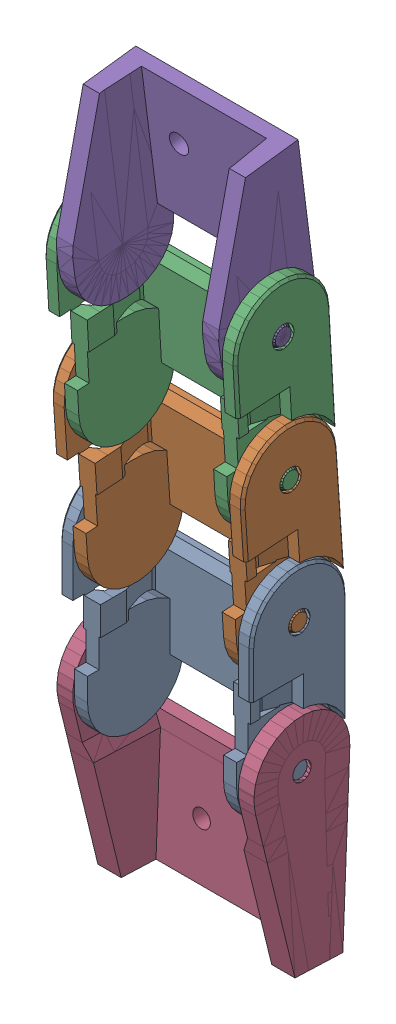
SolidWorks assembly Test Track Assembly, configuration Default. Lengths in mm.
Overall size (24.67 88.78 16.6).
5 component instances, 3 part files, 8 mates.
Components (placement in the parent):
- Main Cable Link-1: Main Cable Link [Default] at origin size (24 28 12)
- Main Cable Link-2: Main Cable Link [Default] at (0 15.9628 1.0904) x (1 0 0) z (0 -0.06815 0.997675) size (24 28 12)
- Main Cable Link-3: Main Cable Link [Default] at (0 31.9368 2.0023) x (1 0 0) z (0 -0.056992 0.998375) size (24 28 12)
- Track End Modified-1: Track End Modified [Default] at (0 15.9747 -1.2712) x (1 0 0) z (0 0.039726 0.999211) size (24.67 28.01 12)
- Track End Modified 2-1: Track End Modified 2 [Default] at (0 31.9368 2.0023) x (1 0 0) z (0 -0.99211 -0.125367) size (24 12.06 24)
Mates (geometry in assembly coordinates):
- Width1: width anti-aligned: plane of Main Cable Link-1 through (-12 0 0) normal (-1 0 0); plane of Main Cable Link-2 through (12 0 0) normal (1 0 0); plane of Main Cable Link-1 through (10.16 15.9628 1.0904) normal (1 0 0); plane of Main Cable Link-2 through (-10.16 15.9628 1.0904) normal (-1 0 0)
- Width2: width anti-aligned: plane of Main Cable Link-2 through (12 15.9628 1.0904) normal (1 0 0); plane of Main Cable Link-3 through (-12 15.9628 1.0904) normal (-1 0 0); plane of Main Cable Link-2 through (-10.16 31.9368 2.0023) normal (-1 0 0); plane of Main Cable Link-3 through (10.16 31.9368 2.0023) normal (1 0 0)
- Width3: width anti-aligned: plane of Main Cable Link-3 through (-12 31.9368 2.0023) normal (-1 0 0); plane of Track End Modified 2-1 through (12 31.9368 2.0023) normal (1 0 0); plane of Main Cable Link-3 through (10.16 31.9368 2.0023) normal (1 0 0); plane of Track End Modified 2-1 through (-10.16 31.9368 2.0023) normal (-1 0 0)
- Width4: width anti-aligned: plane of Track End Modified-1 through (-12.3367 15.9747 -1.2712) normal (-1 0 0); plane of Main Cable Link-1 through (12.3367 15.9747 -1.2712) normal (1 0 0); plane of Track End Modified-1 through (10.16 0 0) normal (1 0 0); plane of Main Cable Link-1 through (-10.16 0 0) normal (-1 0 0)
- Coincident5: coincident anti-aligned: line of Main Cable Link-1 through (-12 0 0) axis (1 0 0); line of Main Cable Link-2 through (12 0 0) axis (-1 0 0)
- Coincident6: coincident anti-aligned: line of Main Cable Link-2 through (-12 15.9628 1.0904) axis (1 0 0); line of Main Cable Link-3 through (12 15.9628 1.0904) axis (-1 0 0)
- Coincident7: coincident anti-aligned: line of Main Cable Link-3 through (-12 31.9368 2.0023) axis (1 0 0); line of Track End Modified 2-1 through (12 31.9368 2.0023) axis (-1 0 0)
- Coincident8: coincident aligned: line of Main Cable Link-1 through (12 -16 0) axis (-1 0 0); line of Track End Modified-1 through (12.3367 -16 0) axis (-1 0 0)
